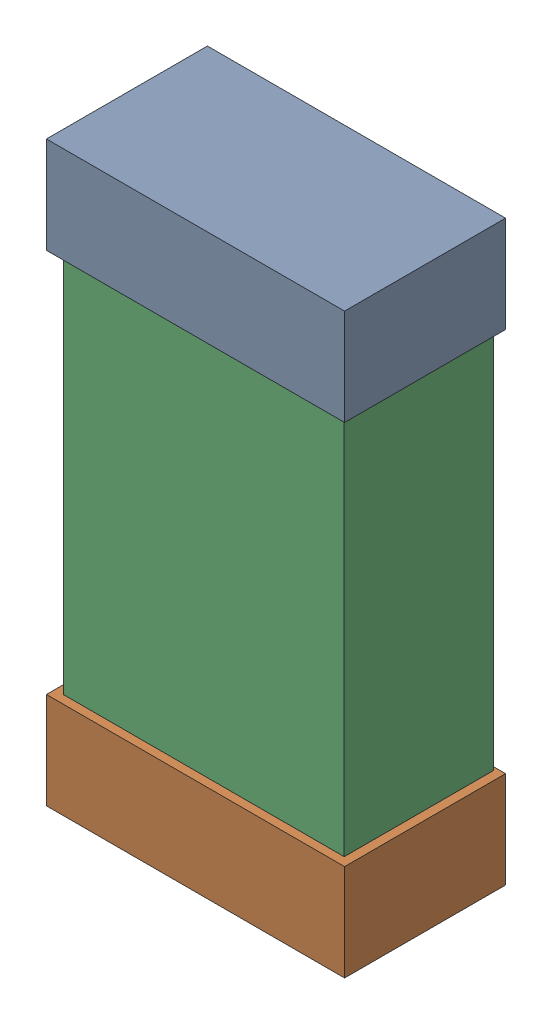
SolidWorks assembly R48, configuration Default. Lengths in mm.
Overall size (0.85 1.65 0.46).
6 component instances, 2 part files, 0 mates.
Components (placement in the parent):
- 432138512_8-1: 432138512_8 [Default] at (38.2834 52.3358 -0.8715) size (0.85 0.28 0.46)
  - Extruded-1: Extruded [Default] at origin size (0.85 0.28 0.46)
- 432138512_9-1: 432138512_9 [Default] at (38.2834 50.9642 -0.8715) size (0.85 0.28 0.46)
  - Extruded-1: Extruded [Default] at origin size (0.85 0.28 0.46)
- 432124816_4-1: 432124816_4 [Default] at (38.2834 51.65 -0.8615) size (0.8 1.5 0.42)
  - Extruded (1)-1: Extruded (1) [Default] at origin size (0.8 1.5 0.42)
